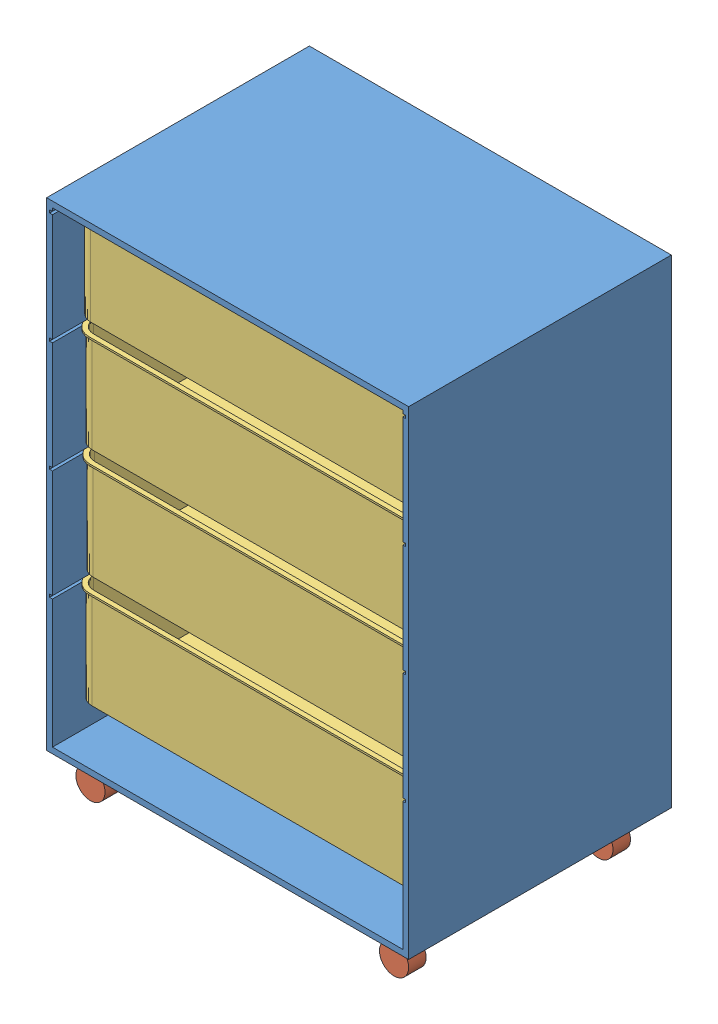
SolidWorks assembly drawers, configuration Default. Lengths in mm.
Overall size (620 892 450).
9 component instances, 3 part files, 13 mates.
Components (placement in the parent):
- drawer-1: drawer [Default] at (-268.0912 -140.2571 236.7567) size (620 820 450)
- rolls-1: rolls [Default] at (281.9088 -197.2571 621.7567) size (50 75 30)
- rolls-2: rolls [Default] at (281.9088 -197.2571 271.7567) size (50 75 30)
- rolls-3: rolls [Default] at (-238.0912 -197.2571 271.7567) size (50 75 30)
- rolls-4: rolls [Default] at (-238.0912 -197.2571 621.7567) size (50 75 30)
- box-1: box [Default] at (-268.0912 482.4435 646.2672) size (610 170 410)
- box-2: box [Default] at (-268.0912 292.4435 644.3936) size (610 170 410)
- box-3: box [Default] at (-268.0912 102.4435 642.5201) size (610 170 410)
- box-4: box [Default] at (-268.0912 -87.5565 644.3936) size (610 170 410)
Mates (geometry in assembly coordinates):
- Coincident1: coincident anti-aligned: plane of drawer-1 through (291.9088 -147.2571 636.7567) normal (0 -1 0); plane of rolls-1 through (291.9088 -147.2571 636.7567) normal (0 1 0)
- Coincident2: coincident anti-aligned: circle of drawer-1; circle of rolls-1
- Coincident3: coincident anti-aligned: circle of drawer-1; circle of rolls-2
- Coincident4: coincident anti-aligned: circle of drawer-1; circle of rolls-3
- Coincident5: coincident anti-aligned: circle of drawer-1; circle of rolls-4
- Coincident6: coincident anti-aligned: plane of drawer-1 through (-273.0912 649.4435 1236.7567) normal (0 1 0); plane of box-1 through (-243.0912 649.4435 271.2672) normal (0 -1 0)
- Coincident7: coincident anti-aligned: line of drawer-1 through (-273.0912 649.4435 686.7567) axis (0 0 -1); line of box-1 through (-273.0912 649.4435 271.2672) axis (0 0 1)
- Coincident8: coincident anti-aligned: plane of drawer-1 through (-273.0912 459.4435 1236.7567) normal (0 1 0); plane of box-2 through (-243.0912 459.4435 269.3936) normal (0 -1 0)
- Coincident9: coincident anti-aligned: line of drawer-1 through (-273.0912 459.4435 686.7567) axis (0 0 -1); line of box-2 through (-273.0912 459.4435 269.3936) axis (0 0 1)
- Coincident10: coincident anti-aligned: plane of drawer-1 through (-273.0912 269.4435 1236.7567) normal (0 1 0); plane of box-3 through (-243.0912 269.4435 267.5201) normal (0 -1 0)
- Coincident11: coincident anti-aligned: line of drawer-1 through (-273.0912 269.4435 686.7567) axis (0 0 -1); line of box-3 through (-273.0912 269.4435 267.5201) axis (0 0 1)
- Coincident12: coincident anti-aligned: plane of drawer-1 through (-273.0912 79.4435 1236.7567) normal (0 1 0); plane of box-4 through (-243.0912 79.4435 269.3936) normal (0 -1 0)
- Coincident13: coincident anti-aligned: line of drawer-1 through (-273.0912 79.4435 686.7567) axis (0 0 -1); line of box-4 through (-273.0912 79.4435 269.3936) axis (0 0 1)
